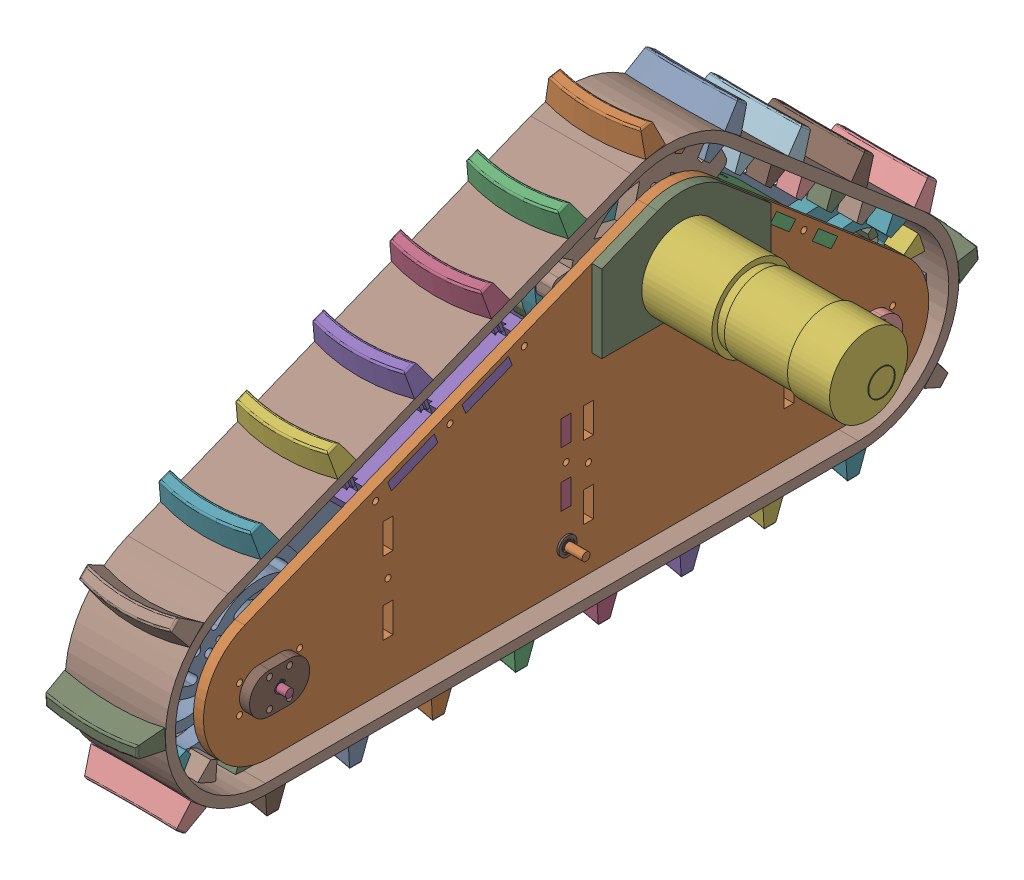
SolidWorks assembly Track-Sx-Dx, configuration Default. Lengths in mm.
Overall size (169.58 204.91 420.3).
61 component instances, 21 part files, 0 mates.
Components (placement in the parent):
- TrackBase-Ext-Dx-1: TrackBase-Ext-Dx [Default] at (-50 33 -53) size (5 147 362)
- TrackBase-Int-Dx-1: TrackBase-Int-Dx [Default] at (0 33 -53) size (5 147 362)
- Track-Spacer_0-Dx-1: Track-Spacer_0-Dx [Default] at (-23.2811 119.1351 -93.9865) x (0 0.64881 0.76095) z (-1 0 0) size (40 5 55)
- Track-Spacer_0-Dx-2: Track-Spacer_0-Dx [Default] at (-23.2811 88.4049 -2.5) x (0 1 0) z (-1 0 0) size (40 5 55)
- Track-Spacer_1-Dx-1: Track-Spacer_1-Dx [Default] at (-23.2811 99.1486 65.4531) x (0 -0.373776 0.927519) z (-1 0 0) size (95 5 55)
- Motor-Dx-1: Motor-Dx [Default] at (103 114 -53) x (-1 0 0) z (0 0 -1) size (112 40.5 40.5)
- Laser_Sprocket-Dx-1: Laser_Sprocket-Dx [Default] at (-97.1863 126.9707 -103.6466) x (1 0 0) z (0 -0.242287 -0.970205) size (59.5 91 91)
  - Laser-Sprocket_Center-Dx-1: Laser-Sprocket_Center-Dx [Default] at (71.1863 24.8553 -45.995) size (8 91 91)
  - Laser-Sprocket_Side-Dx-1: Laser-Sprocket_Side-Dx [Default] at (79.1863 24.8553 -45.995) x (1 0 0) z (0 -1 0) size (8 88.73 90)
  - Laser-Sprocket_Side-Dx-2: Laser-Sprocket_Side-Dx [Default] at (63.1863 24.8553 -45.995) x (1 0 0) z (0 -1 0) size (8 88.73 90)
  - MotorHub-Dx-1: MotorHub-Dx [Default] at (66.6863 24.8553 -45.995) x (0 1 0) z (0 0 1) size (22 13 22)
  - MotorHub-Dx-2: MotorHub-Dx [Default] at (83.6863 24.8553 -45.995) x (0 0 -1) z (0 -1 0) size (22 13 22)
  - SprocketShaft-Dx-1: SprocketShaft-Dx [Default] at (37.1863 24.8553 -45.995) x (1 0 0) z (0 0.285041 -0.958515) size (25 8 8)
- Laser_Sprocket-Passive-Dx-1: Laser_Sprocket-Passive-Dx [Default] at (7.5533 84.5264 136.7429) x (-1 0 0) z (0 0.968226 0.250076) size (75 90 90)
  - Laser-Sprocket_Center-Passive-Dx-1: Laser-Sprocket_Center-Passive-Dx [Default] at (26.0533 23.785 -47.0741) size (8 90 90)
  - Bearing-4mm-Dx-1: Bearing-4mm-Dx [Default] at (34.9674 23.785 -47.0741) size (3.17 9.12 9.12)
  - Bearing-4mm-Dx-2: Bearing-4mm-Dx [Default] at (25.1392 23.785 -47.0741) x (-1 0 0) z (0 0 -1) size (3.17 9.12 9.12)
  - Shaft-4mm-Dx-1: Shaft-4mm-Dx [Default] at (-7.4467 23.785 -47.0741) x (1 0 0) z (0 -0.425008 -0.90519) size (75 4 4)
  - msh_4-Dx-1: msh_4-Dx [Default] at (35.0923 23.785 -47.0741) x (0 0 1) z (0 1 0) size (4.59 0.25 5.77)
  - msh_4-Dx-2: msh_4-Dx [Default] at (25.0143 23.785 -47.0741) x (0 1 0) z (0 0 1) size (4.59 0.25 5.77)
- Laser_Sprocket-Passive-Dx1-1: Laser_Sprocket-Passive-Dx1 [Default] at (7.5533 64.9834 -106.0625) x (-1 0 0) z (0 0.182661 0.983176) size (75 90 90)
  - Laser-Sprocket_Center-Passive-Dx-1: Laser-Sprocket_Center-Passive-Dx [Default] at (26.0533 23.785 -47.0741) size (8 90 90)
  - Bearing-4mm-Dx-1: Bearing-4mm-Dx [Default] at (34.9674 23.785 -47.0741) size (3.17 9.12 9.12)
  - Bearing-4mm-Dx-2: Bearing-4mm-Dx [Default] at (25.1392 23.785 -47.0741) x (-1 0 0) z (0 0 -1) size (3.17 9.12 9.12)
  - Shaft-4mm-Dx-1: Shaft-4mm-Dx [Default] at (-7.4467 23.785 -47.0741) x (1 0 0) z (0 -0.425008 -0.90519) size (75 4 4)
  - msh_4-Dx-1: msh_4-Dx [Default] at (35.0923 23.785 -47.0741) x (0 0 1) z (0 1 0) size (4.59 0.25 5.77)
  - msh_4-Dx-2: msh_4-Dx [Default] at (25.0143 23.785 -47.0741) x (0 1 0) z (0 0 1) size (4.59 0.25 5.77)
- RubberTrack-Dx-1: RubberTrack-Dx [Default] at (-22 33 148) x (0 0 1) z (-1 0 0) size (420.3 204.91 50)
- TrackBase-MotorSupport-Dx-1: TrackBase-MotorSupport-Dx [Default] at (5 33 -53) size (5 52.35 84.4)
- Shaft-Blocker-Dx-1: Shaft-Blocker-Dx [Default] at (5 33 -148) size (5 20 30)
- Shaft-Blocker-Dx-2: Shaft-Blocker-Dx [Default] at (5 33 148) size (5 20 30)
- Shaft-Blocker-Dx-3: Shaft-Blocker-Dx [Default] at (-55 33 148) size (5 20 30)
- Shaft-Blocker-Dx-4: Shaft-Blocker-Dx [Default] at (-55 33 -148) size (5 20 30)
- msh_4-Dx-1: msh_4-Dx [Default] at (-55.125 33 148) x (0 -0.14526 0.989394) z (0 -0.989394 -0.14526) size (4.59 0.25 5.77)
- msh_4-Dx-2: msh_4-Dx [Default] at (-55.125 33 -148) x (0 1 -0.000737) z (0 0.000737 1) size (4.59 0.25 5.77)
- msh_4-Dx-3: msh_4-Dx [Default] at (10.125 33 148) x (0 0.520584 0.853811) z (0 -0.853811 0.520584) size (4.59 0.25 5.77)
- msh_4-Dx-4: msh_4-Dx [Default] at (10.125 33 -148) x (0 -0.619165 -0.785261) z (0 0.785261 -0.619165) size (4.59 0.25 5.77)
- Balancer-Dx-1: Balancer-Dx [Default] at (-75.1134 -75.4575 114.567) size (75 60.41 160.21)
  - Balancer-lateral-Dx-1: Balancer-lateral-Dx [Default] at (57.5274 93.4575 -114.567) size (5 30 130)
  - Balancer-lateral-Dx-2: Balancer-lateral-Dx [Default] at (42.6994 93.4575 -114.567) size (5 30 130)
  - Balancer-Wheel-Dx-1: Balancer-Wheel-Dx [Default] at (48.6134 93.4575 -164.567) x (1 0 0) z (0 0.006923 0.999976) size (8 60 60)
  - Balancer-Wheel-Dx-2: Balancer-Wheel-Dx [Default] at (48.6134 93.4575 -64.567) size (8 60 60)
  - Bearing-4mm-Dx-1: Bearing-4mm-Dx [Default] at (57.5275 93.4575 -164.567) size (3.17 9.12 9.12)
  - Bearing-4mm-Dx-2: Bearing-4mm-Dx [Default] at (47.6994 93.4575 -164.567) x (-1 0 0) z (0 0 -1) size (3.17 9.12 9.12)
  - Bearing-4mm-Dx-3: Bearing-4mm-Dx [Default] at (57.5275 93.4575 -64.567) size (3.17 9.12 9.12)
  - Bearing-4mm-Dx-4: Bearing-4mm-Dx [Default] at (47.6994 93.4575 -64.567) x (-1 0 0) z (0 0 -1) size (3.17 9.12 9.12)
  - Shaft-4mm-Dx-1: Shaft-4mm-Dx [Default] at (15.1134 93.4575 -114.567) x (1 0 0) z (0 -0.936019 -0.351949) size (75 4 4)
  - Balancer-Shaft-4mm-Dx-1: Balancer-Shaft-4mm-Dx [Default] at (41.6134 93.4575 -164.567) size (22 4 4)
  - Balancer-Shaft-4mm-Dx-2: Balancer-Shaft-4mm-Dx [Default] at (41.6134 93.4575 -64.567) size (22 4 4)
  - msh_4-Dx-1: msh_4-Dx [Default] at (62.6524 93.4575 -164.567) x (0 1 0) z (0 0 1) size (4.59 0.25 5.77)
  - msh_4-Dx-2: msh_4-Dx [Default] at (42.5744 93.4575 -164.567) x (0 0.77366 -0.633601) z (0 0.633601 0.77366) size (4.59 0.25 5.77)
  - msh_4-Dx-3: msh_4-Dx [Default] at (62.6524 93.4575 -114.567) x (0 0.995776 -0.091812) z (0 0.091812 0.995776) size (4.59 0.25 5.77)
  - msh_4-Dx-4: msh_4-Dx [Default] at (42.5744 93.4575 -114.567) x (0 1 0) z (0 0 1) size (4.59 0.25 5.77)
  - msh_4-Dx-5: msh_4-Dx [Default] at (62.6524 93.4575 -64.567) x (0 1 0) z (0 0 1) size (4.59 0.25 5.77)
  - msh_4-Dx-6: msh_4-Dx [Default] at (42.5744 93.4575 -64.567) x (0 1 0) z (0 0 1) size (4.59 0.25 5.77)
- Bearing-4mm-Dx-1: Bearing-4mm-Dx [Default] at (5.9141 18 0) x (1 0 0) z (0 -0.946091 0.3239) size (3.17 9.12 9.12)
- msh_4-Dx-5: msh_4-Dx [Default] at (6.039 18 0) x (0 1 0) z (0 0 1) size (4.59 0.25 5.77)
- Bearing-4mm-Dx-2: Bearing-4mm-Dx [Default] at (-50.9141 18 0) x (-1 0 0) z (0 0 1) size (3.17 9.12 9.12)
- msh_4-Dx-6: msh_4-Dx [Default] at (-51.039 18 0) x (0 1 0) z (0 0 1) size (4.59 0.25 5.77)
- AMT102-V-Dx-1: AMT102-V-Dx [Default] at (106.9777 121.6656 -52.3439) x (0 0 1) z (1 0 0) size (13.4 13.4 0.3)
- TrackBase-MotorSupport-Extern-Dx-1: TrackBase-MotorSupport-Extern-Dx [Default] at (-55 33 -53) size (5 62.35 84.4)
